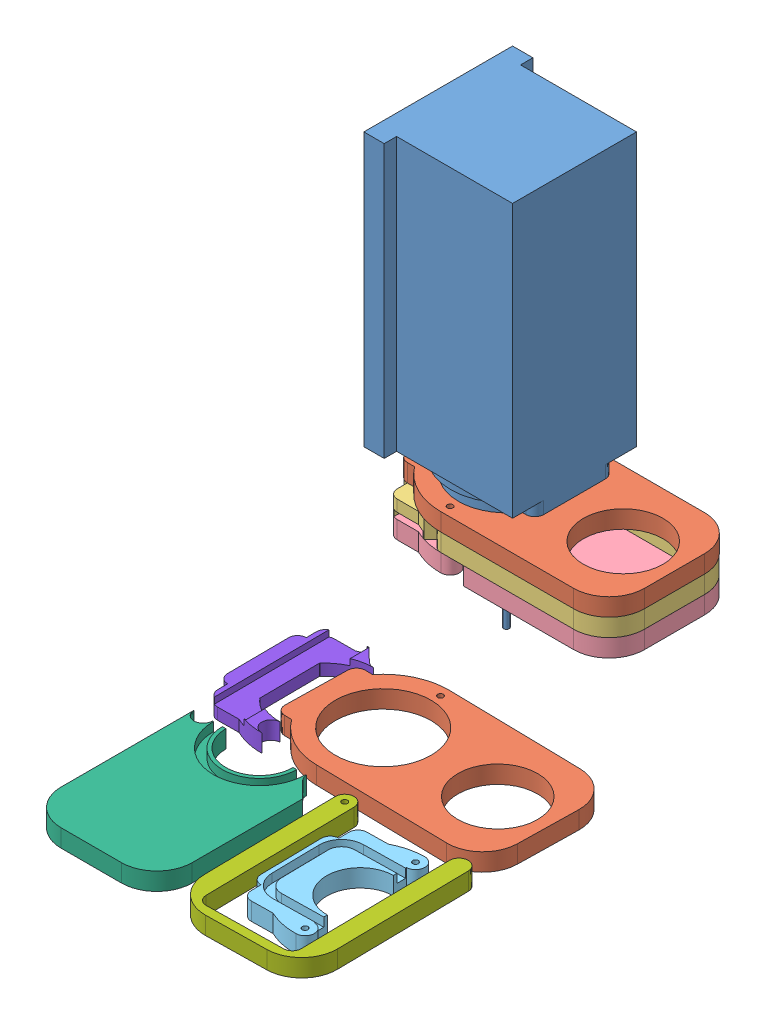
SolidWorks assembly InstallAspiration, configuration Default. Lengths in mm.
Overall size (220.19 317.84 207.93).
10 component instances, 8 part files, 1 mates.
Components (placement in the parent):
- Spindel_simple-1: Spindel_simple [Default] at (48.093 153.22 170.6459) size (77 244 84)
- AspirationTopClamp-1: AspirationTopClamp [По умолчанию] at (0 128.22 0) x (-1 0 0) z (0 -1 0) size (133.5 74 10)
- AspirationMidleClamp-1: AspirationMidleClamp [По умолчанию] at (0 128.22 0) x (-1 0 0) z (0 -1 0) size (133.5 74 10)
- AspirationBottomClamp-1: AspirationBottomClamp [По умолчанию] at (-0.0336 118.22 -2.0214) x (-1 0 0) z (0 -1 0) size (133.51 74 10)
- Сut_10mm-1: Сut_10mm [По умолчанию] at (-13.0069 -0.6195 -5.9761) size (181.54 10 183.56)
  - Body1-1: Body1 [По умолчанию] at (41.9768 -10 458.5612) x (-0.999847 0 0.017511) z (0 1 0) size (43.75 74 10)
  - Body2-1: Body2 [По умолчанию] at (-185.9725 -10 193.5013) x (0 0 -1) z (0 1 0) size (95.01 74 10)
  - Boss-Extrude1-1: Boss-Extrude1 [По умолчанию] at (238.6281 0 192.5633) x (-0.015723 0 -0.999876) z (0 -1 0) size (100.25 74 10)
  - Boss-Extrude2-1: Boss-Extrude2 [По умолчанию] at (-67.1314 -10 367.5458) x (-0.999966 0 0.008235) z (0 1 0) size (38.5 72.29 10)
  - AspirationTopClamp-1: AspirationTopClamp [По умолчанию] at (-39.7662 0 366.4131) x (-0.999808 0 -0.019597) z (0 1 0) size (133.5 74 10)
Mates (geometry in assembly coordinates):
- Coincident13: coincident anti-aligned: plane of AspirationMidleClamp-1 through (0 118.22 0) normal (0 -1 0); plane of AspirationBottomClamp-1 through (-0.0336 118.22 -2.0214) normal (0 1 0)
